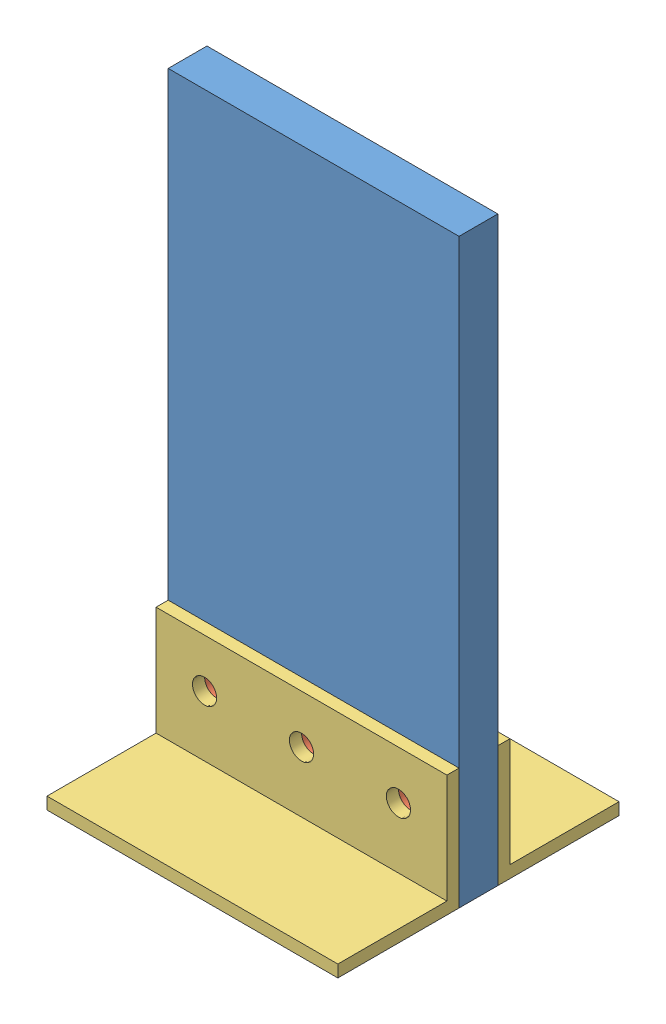
SolidWorks assembly Crush Test, configuration Default. Lengths in mm.
Overall size (76.2 152.4 73.66).
6 component instances, 3 part files, 8 mates.
Components (placement in the parent):
- Flat Carbon Coupon-1: Flat Carbon Coupon [Default] at (20.9271 41.6837 161.6682) size (76.2 152.4 10.16)
- Insert-1: Insert [Default] at (33.6271 60.7337 171.8282) x (1 0 0) z (0 1 0) size (12.7 10.16 12.7)
- Insert-4: Insert [Default] at (84.4271 60.7337 171.8282) x (1 0 0) z (0 1 0) size (12.7 10.16 12.7)
- Insert-8: Insert [Default] at (59.0271 60.7337 171.8282) x (1 0 0) z (0 1 0) size (12.7 10.16 12.7)
- L Bracket-1: L Bracket [Default] at (20.9271 44.8587 158.4932) size (76.2 31.75 31.75)
- L Bracket-2: L Bracket [Default] at (97.1271 44.8587 175.0032) x (-1 0 0) z (0 0 -1) size (76.2 31.75 31.75)
Mates (geometry in assembly coordinates):
- Concentric1: concentric anti-aligned: cylinder of Flat Carbon Coupon-1 through (33.6271 60.7337 171.8282) axis (0 0 -1) radius 6.35; cylinder of Insert-1 through (33.6271 60.7337 161.6682) axis (0 0 1) radius 6.35
- Coincident1: coincident anti-aligned: circle of Flat Carbon Coupon-1; circle of Insert-1
- Coincident4: coincident anti-aligned: circle of Flat Carbon Coupon-1; circle of Insert-8
- Coincident5: coincident anti-aligned: circle of Flat Carbon Coupon-1; circle of Insert-4
- Coincident6: coincident anti-aligned: circle of Insert-1; circle of L Bracket-1
- Concentric4: concentric anti-aligned: cylinder of Insert-4 through (84.4271 60.7337 161.6682) axis (0 0 1) radius 3.175; cylinder of L Bracket-1 through (84.4271 60.7337 234.6932) axis (0 0 -1) radius 3.175
- Coincident8: coincident aligned: circle of Insert-4; circle of L Bracket-2
- Coincident9: coincident aligned: circle of Insert-1; circle of L Bracket-2
